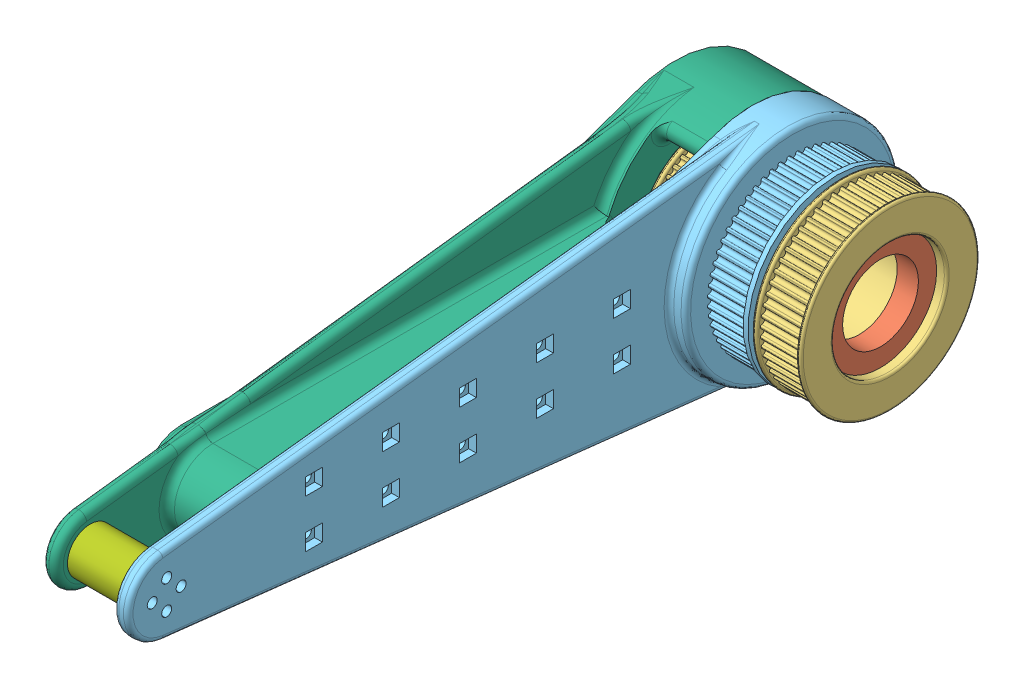
SolidWorks assembly UpperPivotAssem, configuration Default. Lengths in mm.
Overall size (70.97 73.04 249.05).
9 component instances, 7 part files, 28 mates.
Components (placement in the parent):
- Bearing 45_58_7mm-1: Bearing 45_58_7mm [Default] at (10.5875 0 0) x (0 0 -1) z (1 0 0) size (58 58 7)
- Bearing 25_37_7mm-1: Bearing 25_37_7mm [Default] at (45.8625 0 0) size (7 37 37)
- Bearing 25_37_7mm-2: Bearing 25_37_7mm [Default] at (-14.9375 0 0) size (7 37 37)
- 60T 40T htd3mm - Copy-1: 60T 40T htd3mm - Copy [Default] at (44.45 0 0) x (0 0 -1) z (0 1 0) size (58.88 60.62 58.88)
- Part2-1: Part2 [Default] at (-7.4688 0 0) x (0 0 -1) z (0 -1 0) size (31.55 7.94 31.55)
- Bearing 25_37_7mm-3: Bearing 25_37_7mm [Default] at origin size (7 37 37)
- UpperExtremedyDriven 3htd-1: UpperExtremedyDriven 3htd [Default] at (26.9875 0 0) x (0 0 1) z (0 1 0) size (249.05 27.99 71.22)
- outside shield-support-2: outside shield-support [Default] at (-10.16 0 0) size (25.52 73.04 247.46)
- pivot-1: pivot [Default] at (0 0 201) x (0 -1 0) z (0 0 1) size (15 20.63 15)
Mates (geometry in assembly coordinates):
- Coincident23: coincident anti-aligned: plane of Bearing 45_58_7mm-1 through (14.0875 0 0) normal (1 0 0); plane of 60T 40T htd3mm - Copy-1 through (14.0875 0 -22.5) normal (-1 0 0)
- Coincident25: coincident anti-aligned: plane of Bearing 25_37_7mm-1 through (42.3625 0 0) normal (-1 0 0); plane of 60T 40T htd3mm - Copy-1 through (42.3625 0 -18.669) normal (1 0 0)
- Coincident30: coincident: plane of Bearing 25_37_7mm-2 through (-136.85 0 0) normal (1 0 0); plane of Part2-1 through (-136.85 0 0) normal (-1 0 0)
- Coincident31: coincident anti-aligned: plane of Bearing 25_37_7mm-2 through (-11.4375 0 0) normal (1 0 0); plane of Part2-1 through (-11.4375 0 0) normal (-1 0 0)
- Coincident35: coincident anti-aligned: plane of Bearing 25_37_7mm-3 through (3.5 0 0) normal (1 0 0); plane of 60T 40T htd3mm - Copy-1 through (3.5 0 -18.669) normal (-1 0 0)
- Coincident37: coincident anti-aligned: plane of Bearing 25_37_7mm-3 through (-3.5 0 0) normal (-1 0 0); plane of Part2-1 through (-3.5 0 0) normal (1 0 0)
- Concentric1: concentric anti-aligned: cylinder of 60T 40T htd3mm - Copy-1 through (9.5168 0 0) axis (-1 0 0) radius 23.2937
- Concentric2: concentric anti-aligned: cylinder of Bearing 45_58_7mm-1 through (14.0875 0 0) axis (-1 0 0) radius 22.5
- Coincident39: coincident anti-aligned: line of UpperExtremedyDriven 3htd-1 through (30.2875 0 0) axis (-1 0 0)
- Coincident40: coincident anti-aligned: plane of 60T 40T htd3mm - Copy-1 through (0 0 0) normal (-1 0 0)
- Coincident41: coincident anti-aligned: plane of Bearing 45_58_7mm-1 through (14.0875 0 0) normal (1 0 0); plane of UpperExtremedyDriven 3htd-1 through (14.0875 0 0) normal (-1 0 0)
- Coincident42: coincident aligned: plane of 60T 40T htd3mm - Copy-1 through (44.45 0 0) normal (0 1 0)
- Coincident43: coincident aligned: plane of Bearing 45_58_7mm-1 through (10.5875 0 0) normal (0 1 0)
- Coincident44: coincident aligned: plane of Bearing 25_37_7mm-1 through (45.8625 0 0) normal (0 1 0)
- Coincident45: coincident aligned: plane of Bearing 25_37_7mm-2 through (-14.9375 0 0) normal (0 1 0)
- Concentric3: concentric anti-aligned: cylinder of Bearing 25_37_7mm-2 through (-11.4375 0 0) axis (-1 0 0) radius 18.5
- Coincident46: coincident aligned: line of Bearing 25_37_7mm-1 through (0 7.7 42.0125) axis (0 0 1)
- Concentric4: concentric anti-aligned: cylinder of Part2-1 through (-3.5 0 0) axis (-1 0 0) radius 15.775
- Concentric5: concentric anti-aligned: cylinder of Bearing 25_37_7mm-3 through (3.5 0 0) axis (-1 0 0) radius 18.5
- Coincident47: coincident aligned: plane of Bearing 25_37_7mm-3 through (0 0 0) normal (0 1 0)
- Coincident48: coincident anti-aligned: plane of Part2-1 through (-7.4688 0 0) normal (0 -1 0)
- Coincident49: coincident aligned: plane of UpperExtremedyDriven 3htd-1 through (26.9875 0 0) normal (0 1 0)
- Symmetric2: symmetric aligned: plane of UpperExtremedyDriven 3htd-1 through (10.16 0 0) normal (-1 0 0); plane of outside shield-support-2 through (-10.16 0 0) normal (1 0 0)
- Coincident52: coincident: point of outside shield-support-2
- Coincident53: coincident aligned: plane of outside shield-support-2 through (-10.16 0 0) normal (0 1 0)
- Coincident54: coincident aligned: plane of pivot-1 through (0 0 201) normal (1 0 0)
- Concentric6: concentric aligned: circle of UpperExtremedyDriven 3htd-1; cylinder of pivot-1 through (10.3149 0 201) axis (-1 0 0) radius 7.5
- Coincident55: coincident anti-aligned: plane of pivot-1 through (0 0 201) normal (0 -1 0)
